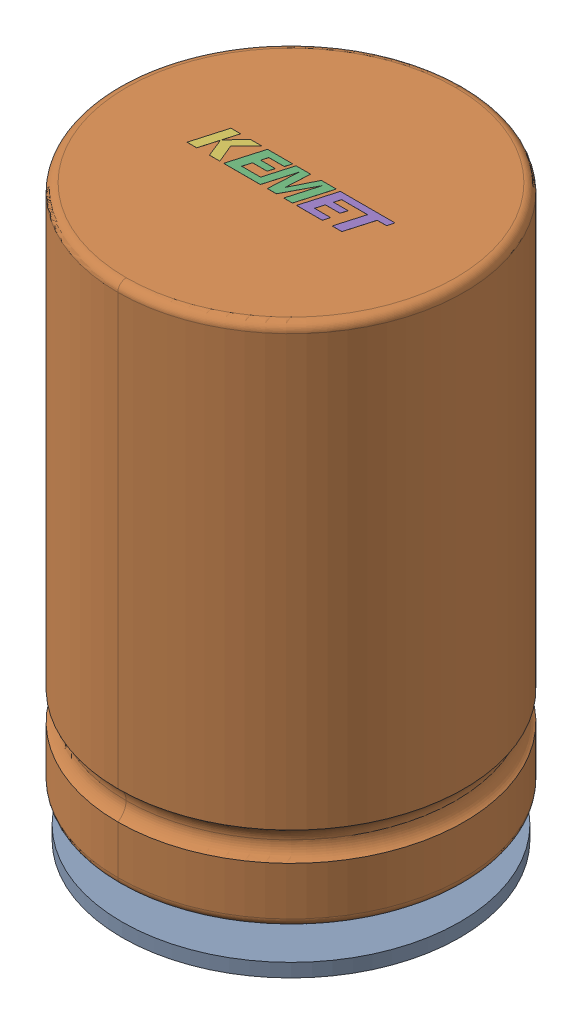
SolidWorks assembly capacitorAssembly, configuration Default. Lengths in mm.
Overall size (41 69.41 41).
2 component instances, 2 part files, 0 mates.
Components (placement in the parent):
- capacitorFootprintPart-1: capacitorFootprintPart [Default] at (660.4366 850.6858 1281.1684) size (40 1.6 40)
- capacitorPart-1: capacitorPart [Default] at (660.4366 854.4861 1281.1684) size (41 69.41 41)
